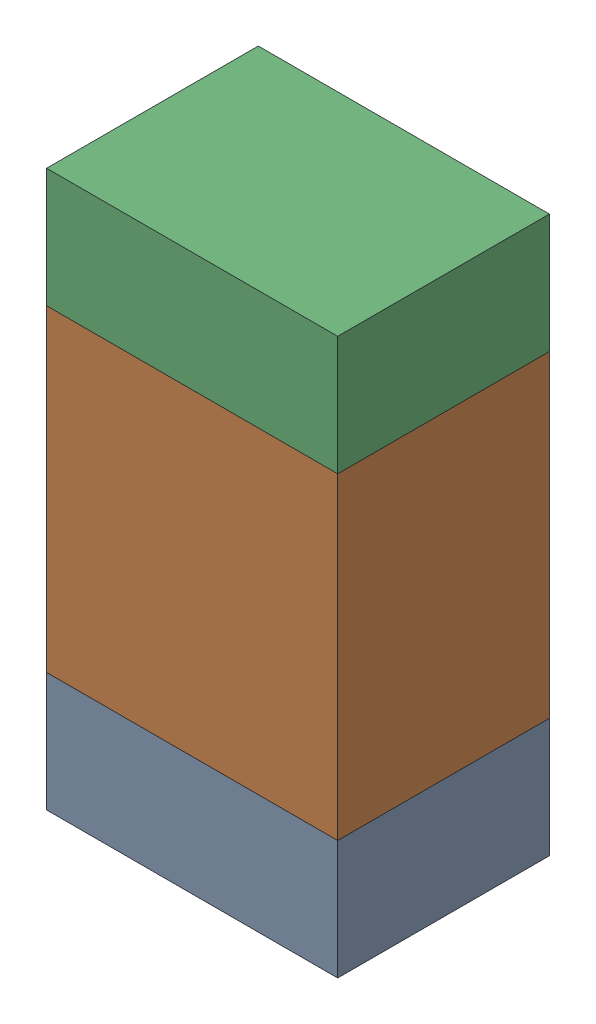
SolidWorks assembly R305_1PCB, configuration Default. Lengths in mm.
Overall size (0.55 1.05 0.4).
6 component instances, 2 part files, 0 mates.
Components (placement in the parent):
- 846483288-1: 846483288 [Default] at (138.8001 117.3874 0) size (0.55 0.22 0.4)
  - Extruded_12-1: Extruded_12 [Default] at origin size (0.55 0.22 0.4)
- 846483424-1: 846483424 [Default] at (138.8001 117.7999 0) size (0.55 0.6 0.4)
  - Extruded_13-1: Extruded_13 [Default] at origin size (0.55 0.6 0.4)
- 846483288-2: 846483288 [Default] at (138.8001 118.2124 0) size (0.55 0.22 0.4)
  - Extruded_12-1: Extruded_12 [Default] at origin size (0.55 0.22 0.4)
